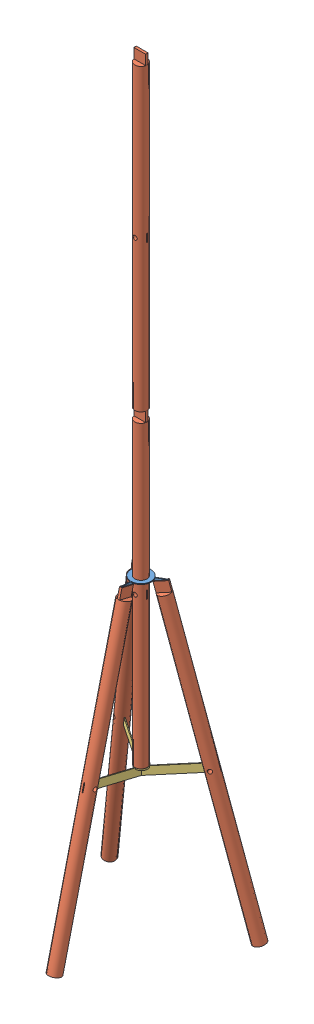
SolidWorks assembly Tripod, configuration Default. Lengths in mm.
Overall size (523.25 2384.07 508.7).
7 component instances, 3 part files, 16 mates.
Components (placement in the parent):
- top connection-1: top connection [Default] at (36.0737 54.7417 50.8847) size (112.75 50.23 97.64)
- long bars-2: long bars [Default] at (36.0737 -421.97 213.1514) x (0 0.232932 0.972493) z (-1 0 0) size (38.1 971.8 38.1)
- long bars-3: long bars [Default] at (177.2358 -421.97 -31.3485) x (0.842204 0.232932 -0.486246) z (0.5 0 0.866025) size (38.1 971.8 38.1)
- long bars-4: long bars [Default] at (-105.0884 -421.97 -31.3485) x (0.842204 -0.232932 0.486246) z (-0.5 0 0.866025) size (38.1 971.8 38.1)
- middle hub-1: middle hub [Default] at (36.7087 -473.8955 49.7849) x (-0.5 0 -0.866025) z (0.866025 0 -0.5) size (302.03 66.82 261.56)
- long bars-5: long bars [Default] at (36.0737 26.9925 50.8847) size (38.1 971.8 38.1)
- long bars-6: long bars [Default] at (36.0737 998.7965 50.8847) size (38.1 971.8 38.1)
Mates (geometry in assembly coordinates):
- Coincident7: coincident anti-aligned: plane of top connection-1 through (37.3437 69.9817 114.5117) normal (0 -0.972493 0.232932); plane of long bars-2 through (36.0737 65.634 96.3601) normal (0 0.972493 -0.232932)
- Width2: width anti-aligned: plane of top connection-1 through (37.3437 54.7417 50.8847) normal (1 0 0); plane of top connection-1 through (34.8037 54.7417 50.8847) normal (-1 0 0); plane of long bars-2 through (32.2637 -883.7881 304.5735) normal (-1 0 0); plane of long bars-2 through (39.8837 -883.7881 304.5735) normal (1 0 0)
- Coincident10: coincident anti-aligned: plane of top connection-1 through (-20.2989 69.9817 19.0712) normal (-0.201725 -0.972493 -0.116466); plane of long bars-4 through (-3.9441 65.634 27.0472) normal (0.201725 0.972493 0.116466)
- Width1: width anti-aligned: plane of long bars-4 through (-213.7968 -875.0927 -98.5107) normal (0.5 0 -0.866025); plane of long bars-4 through (-217.6068 -875.0927 -91.9116) normal (-0.5 0 0.866025); plane of top connection-1 through (34.8037 54.7417 50.8847) normal (-0.5 0 0.866025); plane of top connection-1 through (36.0737 54.7417 48.685) normal (0.5 0 -0.866025)
- Coincident14: coincident anti-aligned: line of long bars-4 through (-17.7589 69.9817 14.6718) axis (-0.5 0 0.866025); line of top connection-1 through (-20.2989 69.9817 19.0712) axis (0.5 0 -0.866025)
- Coincident15: coincident anti-aligned: plane of top connection-1 through (91.1763 69.9817 16.8715) normal (0.201725 -0.972493 -0.116466); plane of long bars-3 through (76.0915 65.634 27.0472) normal (-0.201725 0.972493 0.116466)
- Coincident16: coincident anti-aligned: line of top connection-1 through (91.1763 69.9817 16.8715) axis (0.5 0 0.866025); line of long bars-3 through (93.7163 69.9817 21.2709) axis (-0.5 0 -0.866025)
- Width3: width anti-aligned: plane of top connection-1 through (36.0737 54.7417 48.685) normal (-0.5 0 -0.866025); plane of top connection-1 through (37.3437 54.7417 50.8847) normal (0.5 0 0.866025); plane of long bars-3 through (258.3146 -883.7881 -73.7599) normal (0.5 0 0.866025); plane of long bars-3 through (254.5046 -883.7881 -80.359) normal (-0.5 0 -0.866025)
- Coincident19: coincident anti-aligned: plane of long bars-2 through (34.8037 -438.7581 197.5837) normal (1 0 0); plane of middle hub-1 through (34.8037 -473.8955 50.8847) normal (-1 0 0)
- Coincident20: coincident anti-aligned: plane of long bars-2 through (34.8037 -438.7581 197.5837) normal (0 0.972493 -0.232932); plane of middle hub-1 through (34.8037 -473.8955 50.8847) normal (0 -0.972493 0.232932)
- Coincident21: coincident anti-aligned: line of top connection-1 through (37.3437 69.9817 114.5117) axis (-1 0 0); line of long bars-2 through (32.2637 69.9817 114.5117) axis (1 0 0)
- Coincident23: coincident anti-aligned: plane of long bars-4 through (-124.3293 -429.8833 -40.9907) normal (0.201725 0.972493 0.116466); plane of middle hub-1 through (36.0737 -473.8955 48.685) normal (-0.201725 -0.972493 -0.116466)
- Concentric1: concentric anti-aligned: cylinder of top connection-1 through (36.0737 67.4417 50.8847) axis (0 1 0) radius 19.05; cylinder of long bars-5 through (36.0737 497.4005 50.8847) axis (0 -1 0) radius 19.05
- Coincident25: coincident anti-aligned: plane of middle hub-1 through (36.7087 -443.4155 49.7849) normal (0 1 0); plane of long bars-5 through (36.0737 -443.4155 50.8847) normal (0 -1 0)
- Concentric2: concentric aligned: cylinder of long bars-5 through (36.0737 497.4005 50.8847) axis (0 -1 0) radius 19.05; cylinder of long bars-6 through (36.0737 1469.2045 50.8847) axis (0 -1 0) radius 19.05
- Coincident26: coincident anti-aligned: plane of long bars-5 through (36.0737 528.3885 50.8847) normal (0 1 0); plane of long bars-6 through (36.0737 528.3885 50.8847) normal (0 -1 0)
